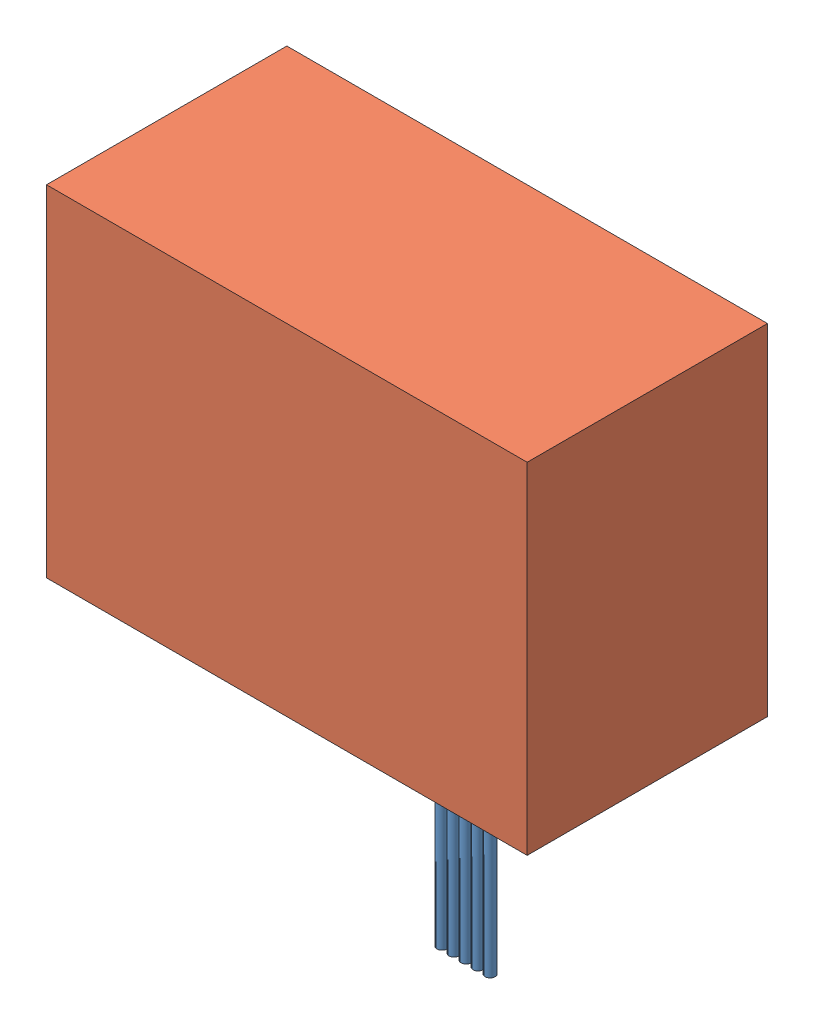
SolidWorks assembly stepper_holder, configuration Default. Lengths in mm.
Overall size (48 64 31.52).
2 component instances, 2 part files, 3 mates.
Components (placement in the parent):
- Step Motor (28BYJ-48)-1: Step Motor (28BYJ-48) [Varsayılan] at (19.2409 45.9228 39.1125) size (42 61 29.02)
- stepper_holder_28BYJ-48-1: stepper_holder_28BYJ-48 [Default] at (19.2409 28.9228 46.0671) size (48 34 24)
Mates (geometry in assembly coordinates):
- Coincident1: coincident: plane of Step Motor (28BYJ-48)-1 through (26.5409 28.9228 55.8125) normal (0 -1 0); plane of stepper_holder_28BYJ-48-1 through (19.2409 28.9228 46.0671) normal (0 -1 0)
- Distance1: distance = 0.5 mm: plane of Step Motor (28BYJ-48)-1 through (19.2409 45.9228 39.1125) normal (0 0 -1); plane of stepper_holder_28BYJ-48-1 through (-4.7591 62.9228 38.6125) normal (0 0 1)
- Distance2: distance = 1 mm: plane of stepper_holder_28BYJ-48-1 through (41.2409 62.9228 36.6125) normal (-1 0 0); moEndPointRef_w of Step Motor (28BYJ-48)-1
